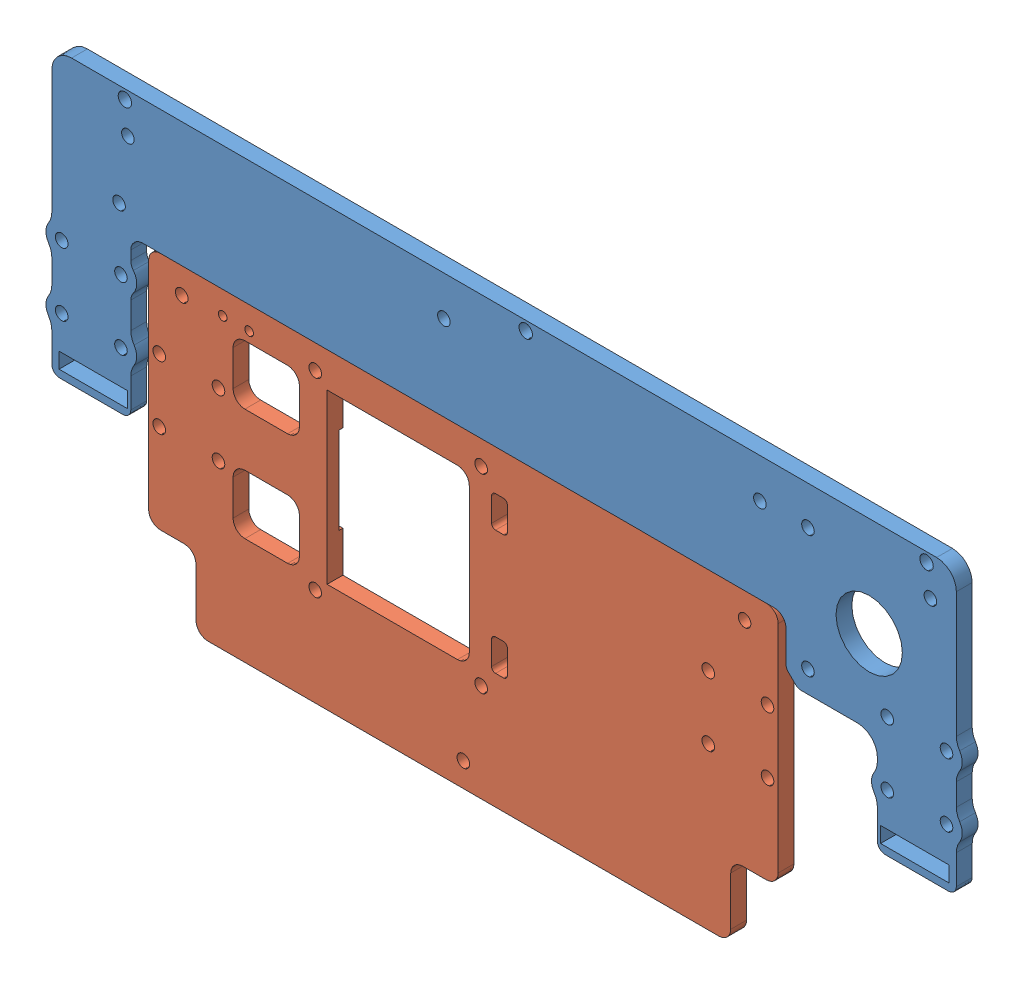
SolidWorks assembly SUB X, configuration Default. Lengths in mm.
Overall size (232 135.83 4).
2 component instances, 2 part files, 2 mates.
Components (placement in the parent):
- X Bridge 4-1: X Bridge 4 [Valor predeterminado] at origin size (232 71.67 4)
- Bed Support2-1: Bed Support2 [Default] at (-109.8598 -28.4017 0) size (159.38 135.83 4)
Mates (geometry in assembly coordinates):
- Distance2: distance = 3 mm: cylinder of X Bridge 4-1 through (-97.5489 32.6773 4) axis (0 0 -1) radius 4; plane of Bed Support2-1 through (-90.5489 1.2961 -6) normal (-1 0 0)
- Coincident2: coincident aligned: plane of X Bridge 4-1 through (0 0 4) normal (0 0 1); plane of Bed Support2-1 through (-109.8598 -28.4017 4) normal (0 0 1)
